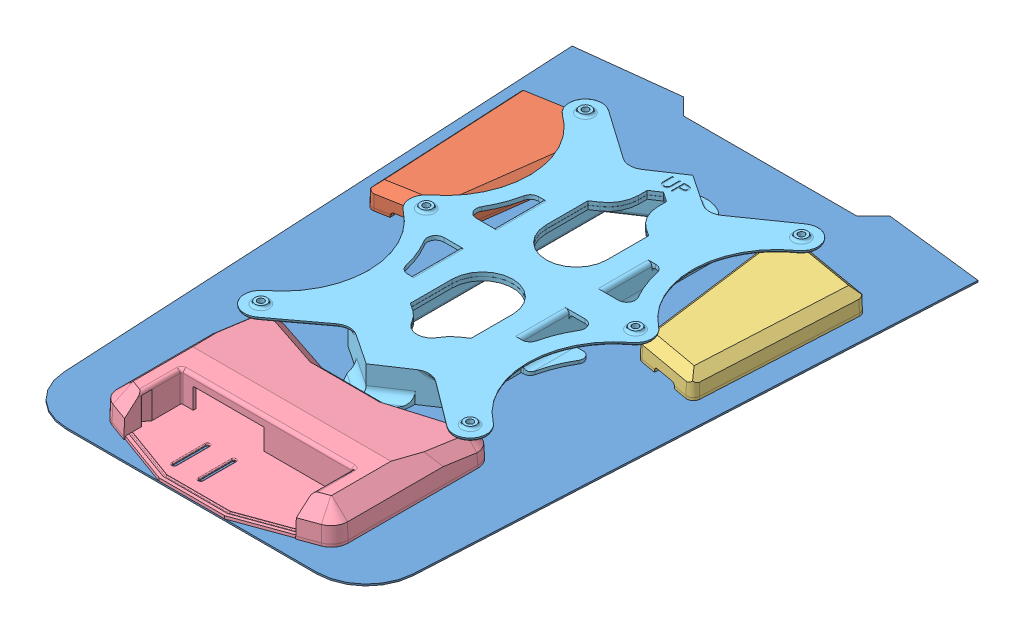
SolidWorks assembly Backpack_Assm, configuration Default. Lengths in mm.
Overall size (311.88 29.84 457.2).
5 component instances, 5 part files, 16 mates.
Components (placement in the parent):
- Back_plate_guess-1: Back_plate_guess [Default] at (1.6149 -5.3286 -29.4134) size (311.88 1.27 457.2)
- UpperBack_L-1: UpperBack_L [Default] at (-129.3994 -4.0586 -88.1783) x (0.998618 0 -0.052559) z (0 1 0) size (71.69 132.36 17.78)
- UpperBack_R-3: UpperBack_R [Default] at (132.6292 -4.0586 -83.329) x (0.998618 0 0.052559) z (0 1 0) size (71.69 132.36 17.78)
- Lower Back_forWireless-1: Lower Back_forWireless [Default] at (1.6149 -4.0586 177.2744) x (1 0 0) z (0 0 -1) size (177.66 25.41 143.67)
- MSI-1: MSI [Default] at (1.6149 -13.2846 -58.0139) x (1 0 0) z (0 1 0) size (292.1 397.53 66.67)
Mates (geometry in assembly coordinates):
- Coincident1: coincident anti-aligned: plane of Back_plate_guess-1 through (97.8148 -4.0586 192.8366) normal (0 1 0); plane of UpperBack_L-1 through (-127.7179 -4.0586 -152.8827) normal (0 -1 0)
- Parallel1: parallel aligned: line of Back_plate_guess-1 through (-154.3247 -4.0586 -217.3161) axis (0.052559 0 0.998618); line of UpperBack_L-1 through (-131.7054 -2.0266 -152.6729) axis (0.052559 0 0.998618)
- Distance1: distance = 63.5 mm: point of UpperBack_L-1; point of Back_plate_guess-1
- Coincident10: coincident anti-aligned: plane of Back_plate_guess-1 through (97.8148 -4.0586 192.8366) normal (0 1 0); plane of UpperBack_R-3 through (130.9477 -4.0586 -148.0334) normal (0 -1 0)
- Parallel3: parallel anti-aligned: line of Back_plate_guess-1 through (135.8621 -4.0586 194.8391) axis (0.052559 0 -0.998618); line of UpperBack_R-3 through (135.1127 -4.0586 -147.8142) axis (-0.052559 0 0.998618)
- Distance4: distance = 63.5 mm: point of UpperBack_R-3; point of Back_plate_guess-1
- Distance5: distance = 127 mm: point of UpperBack_R-3; point of UpperBack_L-1
- Coincident16: coincident anti-aligned: plane of Back_plate_guess-1 through (97.8148 -4.0586 192.8366) normal (0 1 0); plane of Lower Back_forWireless-1 through (1.6149 -4.0586 177.2744) normal (0 -1 0)
- Parallel4: parallel: line of Back_plate_guess-1 through (-94.585 -4.0586 230.9366) axis (1 0 0); line of Lower Back_forWireless-1 through (27.0274 -4.0586 104.9168) axis (-1 0 0)
- Coincident21: coincident: moEndPointRef_w of Back_plate_guess-1; moEndPointRef_w of Lower Back_forWireless-1
- Coincident22: coincident anti-aligned: plane of Back_plate_guess-1 through (97.8148 -5.3286 192.8366) normal (0 -1 0); plane of ? through (-23.7851 -5.3286 46.7866) normal (0 1 0)
- Coincident23: coincident aligned: line of Back_plate_guess-1 through (39.7149 -5.3286 65.8366) axis (0 0 -1); line of ? through (39.7149 -5.3286 65.8366) axis (0 0 -1)
- Coincident25: coincident: point of Back_plate_guess-1; point of ?
- Coincident30: coincident anti-aligned: plane of Back_plate_guess-1 through (97.8148 -4.0586 192.8366) normal (0 1 0); plane of ? through (1.598 -4.0586 -29.4114) normal (0 -1 0)
- Coincident31: coincident anti-aligned: plane of Back_plate_guess-1 through (97.8148 -5.3286 192.8366) normal (0 -1 0); plane of MSI-1 through (1.6149 -5.3286 -58.0139) normal (0 1 0)
- Coincident36: coincident: point of Back_plate_guess-1; line of MSI-1 through (1.6149 14.5543 -149.2822) axis (0 -0.99912 -0.041933)
